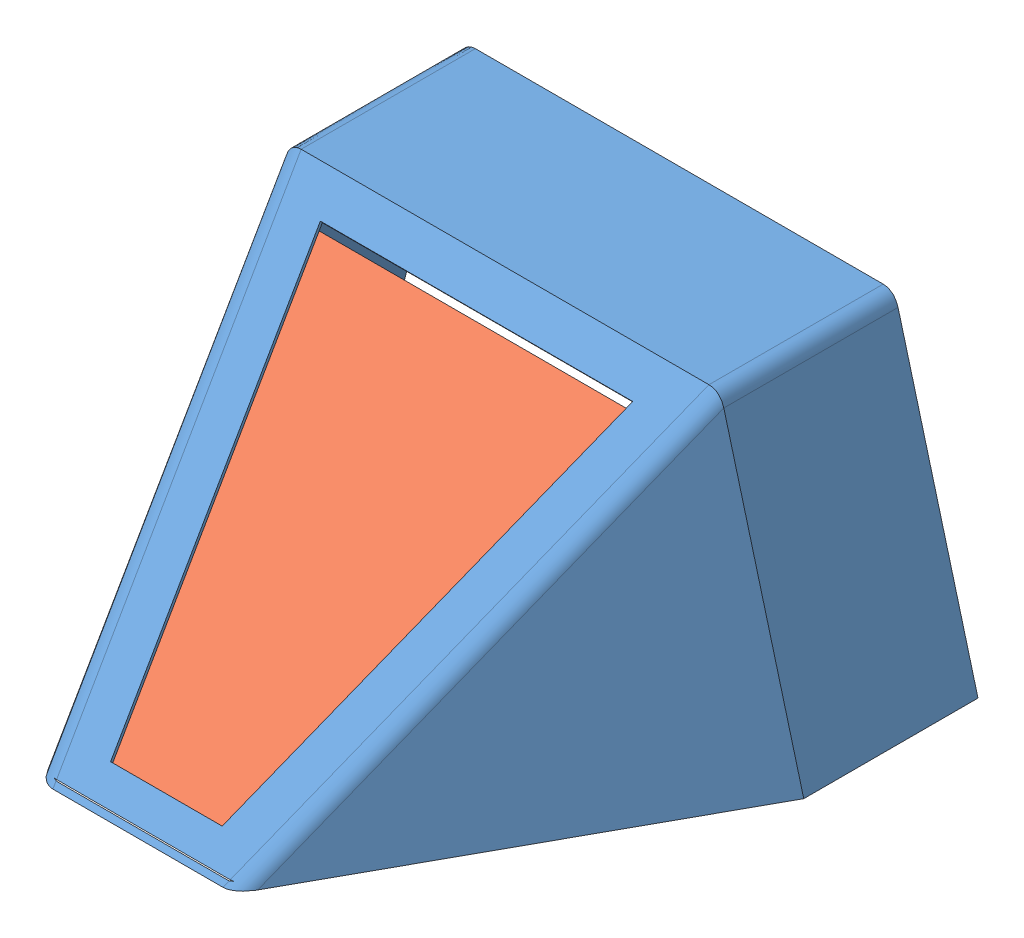
SolidWorks assembly back shell, configuration Default. Lengths in mm.
Overall size (609.6 318.58 552.45).
2 component instances, 2 part files, 0 mates.
Components (placement in the parent):
- back shell-1-1: back shell-1 [Default] at origin size (609.6 318.58 552.45)
- back window-1-1: back window-1 [Default] at (0 15.3827 351.5875) x (-1 0 0) z (0 -0.762896 -0.646522) size (355.6 419.1 1.59)
